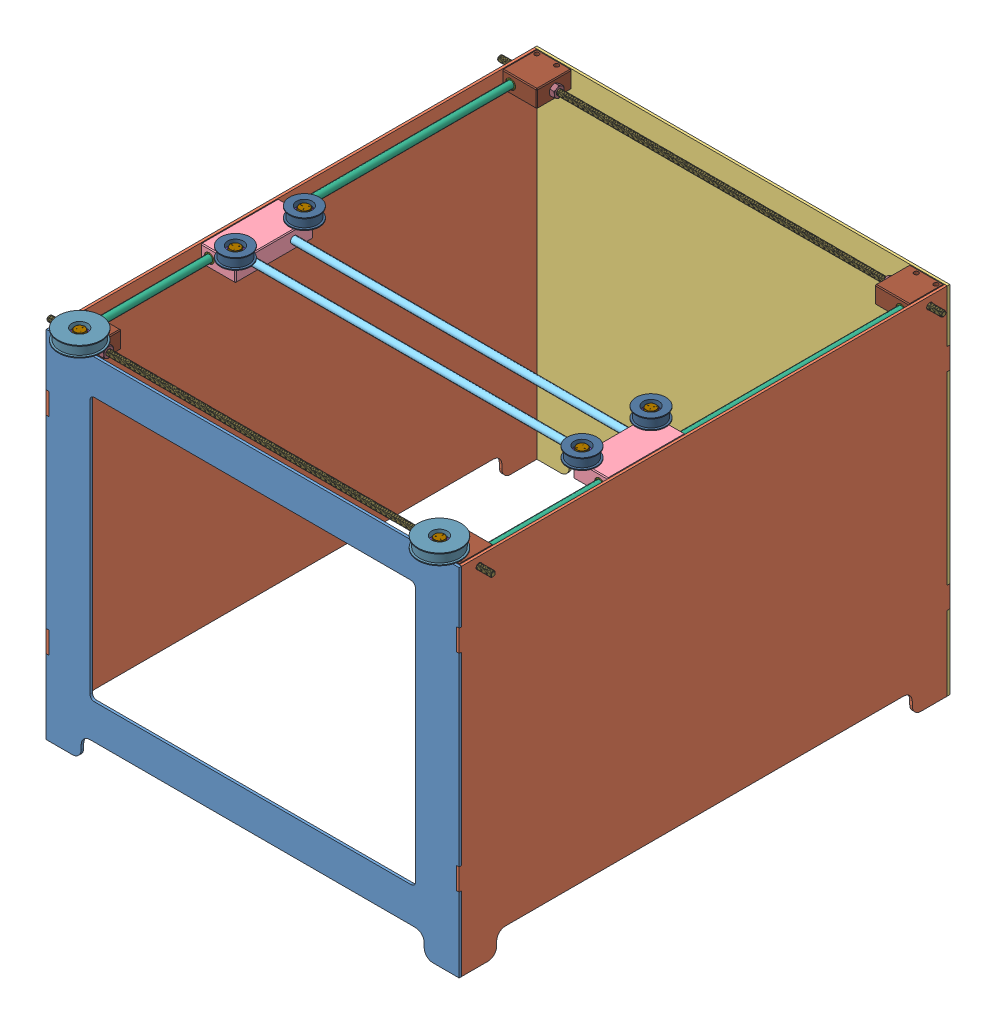
SolidWorks assembly Complete, configuration Default. Lengths in mm.
Overall size (510.38 419.06 587.75).
48 component instances, 14 part files, 3 mates.
Components (placement in the parent):
- Case-1: Case [Default] at (109.9821 167.5568 568.2737) size (472.2 406.4 561.1)
  - Front-1: Front [Default] at (23.422 2.3824 -15.428) size (472.2 406.4 2.9)
  - Side-1: Side [Default] at (-212.678 2.3824 -293.078) size (2.9 406.4 561.1)
  - Side-2: Side [Default] at (256.622 2.3824 -293.078) size (2.9 406.4 561.1)
  - Back-1: Back [Default] at (23.422 2.3824 -573.628) size (472.2 406.4 2.9)
- floating gantry-1: floating gantry [Default] at (327.3323 341.5073 273.483) x (0 0 -1) z (1 0 0) size (584.85 32.66 510.38)
  - end_blocks-1: end_blocks [Default] at (-64.3718 11.6319 19.2717) size (88.9 20 40)
  - end_blocks-2: end_blocks [Default] at (-64.3718 11.6319 -407.1283) x (-1 0 0) z (0 0 -1) size (88.9 20 40)
  - 16in_shaft-1: 16in_shaft [Default] at (-41.8718 21.6319 -397.1283) x (1 0 0) z (0 -1 0) size (8 406.4 8)
  - 16in_shaft-2: 16in_shaft [Default] at (-86.8718 21.6319 -397.1283) x (1 0 0) z (0 -1 0) size (8 406.4 8)
  - 19.5in_shaft-1: 19.5in_shaft [Default] at (-249.3627 21.6319 29.2717) x (0 -0.118278 0.992981) z (0 0.992981 0.118278) size (8 495.3 8)
  - 19.5in_shaft-2: 19.5in_shaft [Default] at (-249.3627 21.6319 -417.1283) x (0 -0.75376 -0.65715) z (0 -0.65715 0.75376) size (8 495.3 8)
  - brass_bushing-1: brass_bushing [Default] at (-29.9218 21.6319 29.2717) x (0 -1 0) z (0 0 1) size (11.2 10 11.2)
  - brass_bushing-2: brass_bushing [Default] at (-98.8218 21.6319 29.2717) x (0 1 0) z (0 0 1) size (11.2 10 11.2)
  - brass_bushing-3: brass_bushing [Default] at (-98.8218 21.6319 -417.1283) x (0 1 0) z (0 0 1) size (11.2 10 11.2)
  - brass_bushing-4: brass_bushing [Default] at (-19.9218 21.6319 -417.1283) x (0 1 0) z (0 0 1) size (11.2 10 11.2)
  - BALL BEARING-1: BALL BEARING [5972K501] at (-103.8218 35.1319 -392.1283) x (1 0 0) z (0 1 0) size (22 22 7)
  - BALL BEARING-2: BALL BEARING [5972K501] at (-24.9218 35.1319 -392.1283) x (1 0 0) z (0 1 0) size (22 22 7)
  - BALL BEARING-3: BALL BEARING [5972K501] at (-103.8218 35.1319 4.2717) x (-1 0 0) z (0 1 0) size (22 22 7)
  - BALL BEARING-4: BALL BEARING [5972K501] at (-24.9218 35.1319 4.2717) x (1 0 0) z (0 1 0) size (22 22 7)
  - Bolt-1: Bolt [92865A542] at (-103.8218 28.1147 -392.1283) x (0 -1 0) z (1 0 0) size (30.4 12.83 11.11)
  - Bolt-2: Bolt [92865A542] at (-24.9218 28.1147 -392.1283) x (0 -1 0) z (1 0 0) size (30.4 12.83 11.11)
  - Bolt-3: Bolt [92865A542] at (-24.9218 28.1147 4.2717) x (0 -1 0) z (1 0 0) size (30.4 12.83 11.11)
  - Bolt-4: Bolt [92865A542] at (-103.8218 28.1147 4.2717) x (0 -1 0) z (-1 0 0) size (30.4 12.83 11.11)
  - 30mm_Pulley-1: 30mm_Pulley [Default] at (-24.9218 43.2919 -392.1283) x (0.837169 0 0.546944) z (0.546944 0 -0.837169) size (34 12.66 34)
  - 30mm_Pulley-2: 30mm_Pulley [Default] at (-103.8218 43.2919 -392.1283) x (0.837169 0 0.546944) z (0.546944 0 -0.837169) size (34 12.66 34)
  - 30mm_Pulley-3: 30mm_Pulley [Default] at (-103.8218 43.2919 4.2717) x (0.837169 0 0.546944) z (0.546944 0 -0.837169) size (34 12.66 34)
  - 30mm_Pulley-4: 30mm_Pulley [Default] at (-24.9218 43.2919 4.2717) x (-0.837169 0 -0.546944) z (-0.546944 0 0.837169) size (34 12.66 34)
  - corner_block-1: corner_block [Default] at (255.9373 11.6319 -407.1283) size (40 20 40)
  - corner_block-2: corner_block [Default] at (-259.3627 31.6319 -407.1283) x (-1 0 0) z (0 0 1) size (40 20 40)
  - corner_block-3: corner_block [Default] at (-259.3627 11.6319 19.2717) x (-1 0 0) z (0 0 -1) size (40 20 40)
  - corner_block-4: corner_block [Default] at (255.9373 31.6319 19.2717) x (1 0 0) z (0 0 -1) size (40 20 40)
  - brass_bushing-5: brass_bushing [Default] at (-249.3627 21.6319 29.2717) x (0 -0.381849 0.924225) z (0 0.924225 0.381849) size (11.2 10 11.2)
  - brass_bushing-6: brass_bushing [Default] at (-249.3627 21.6319 -417.1283) x (0 -0.381849 0.924225) z (0 0.924225 0.381849) size (11.2 10 11.2)
  - brass_bushing-7: brass_bushing [Default] at (245.9373 21.6319 -417.1283) x (0 1 0) z (0 0 1) size (11.2 10 11.2)
  - brass_bushing-8: brass_bushing [Default] at (245.9373 21.6319 29.2717) x (0 1 0) z (0 0 1) size (11.2 10 11.2)
  - Threaded_rod_20in-1: Threaded_rod_20in [99065A120] at (255.9373 21.6319 -195.6783) x (0 0 -1) z (0.910773 0.412908 0) size (510.38 6.43 7.33)
  - Threaded_rod_20in-2: Threaded_rod_20in [99065A120] at (-259.3627 21.6319 -195.6783) x (0 0 -1) z (0.20061 0.979671 0) size (510.38 6.43 7.33)
  - HEX NUT-2: HEX NUT [95505A601] at (-259.3627 21.6319 -384.3502) size (11.11 12.83 7.14)
  - HEX NUT-3: HEX NUT [95505A601] at (-259.3627 21.6319 -3.5064) size (11.11 12.83 7.14)
  - HEX NUT-6: HEX NUT [95505A601] at (255.9373 21.6319 -384.3502) size (11.11 12.83 7.14)
  - HEX NUT-7: HEX NUT [95505A601] at (255.9373 21.6319 -3.5064) size (11.11 12.83 7.14)
  - Bolt-5: Bolt [92865A542] at (-274.3627 28.1147 11.7717) x (0 -1 0) z (0 0 1) size (30.4 12.83 11.11)
  - BALL BEARING-5: BALL BEARING [5972K501] at (-274.3627 35.1319 11.7717) x (0 0 1) z (0 1 0) size (22 22 7)
  - Bolt-6: Bolt [92865A542] at (-274.3627 28.1147 -399.6283) x (0 -1 0) z (0 0 1) size (30.4 12.83 11.11)
  - BALL BEARING-6: BALL BEARING [5972K501] at (-274.3627 35.1319 -399.6283) x (0 0 1) z (0 1 0) size (22 22 7)
  - 45mm_Pulley-1: 45mm_Pulley [Default] at (-274.3627 43.2919 11.7717) x (-0.75801 0 -0.652243) z (-0.652243 0 0.75801) size (49 12.66 49)
  - 45mm_Pulley-2: 45mm_Pulley [Default] at (-274.3627 43.2919 -399.6283) x (0.648677 0 0.761064) z (0.761064 0 -0.648677) size (49 12.66 49)
Mates (geometry in assembly coordinates):
- Coincident1: coincident anti-aligned: plane of Case-1/Front-1 through (-72.696 -23.2608 552.8457) normal (0 0 -1); plane of floating gantry-1/corner_block-3 through (326.604 373.1392 552.8457) normal (0 0 1)
- Coincident2: coincident anti-aligned: plane of Case-1/Side-2 through (366.604 -23.2608 522.8457) normal (-1 0 0); plane of floating gantry-1/corner_block-3 through (366.604 373.1392 512.8457) normal (1 0 0)
- Coincident3: coincident aligned: plane of Case-1/Front-1 through (-102.696 373.1392 555.7457) normal (0 1 0); plane of floating gantry-1/corner_block-3 through (346.604 373.1392 532.8457) normal (0 1 0)
